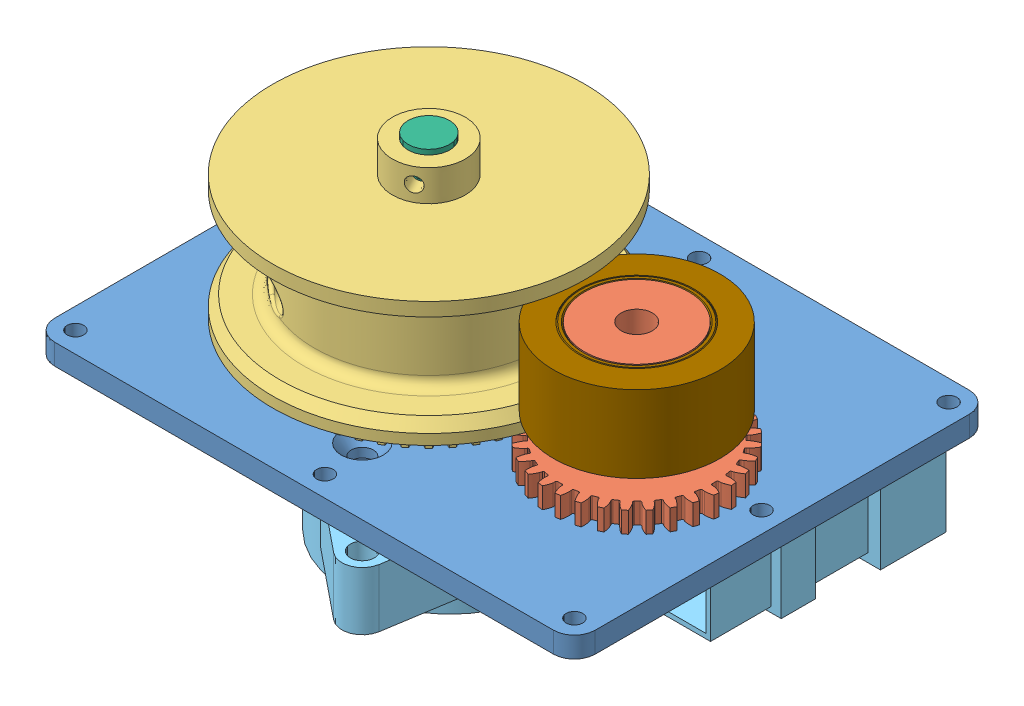
SolidWorks assembly DualRollerWinch, configuration Default. Lengths in mm.
Overall size (166.05 109.39 150.81).
9 component instances, 9 part files, 23 mates.
Components (placement in the parent):
- GearedWinchBaseplate-1: GearedWinchBaseplate [Default] at origin size (165.1 15.88 127)
- GearedWinchRoller-1: GearedWinchRoller [6325K18] at (44.45 6.35 6.35) x (-0.239605 0 0.97087) z (0 -1 0) size (54.09 54.09 37.12)
- GearedDrum-1: GearedDrum [6325K21] at (-19.05 12.7 6.35) x (0.881849 0 -0.471533) z (0 1 0) size (95.25 95.25 53.98)
- 13125K81 Chemical Resistant Shaft Seal-1: 13125K81 Chemical Resistant Shaft Seal [Default] at (-19.05 3.175 6.35) x (0.899798 0 0.436307) z (-0.436307 0 0.899798) size (17.46 3.17 17.46)
- 82-17001-1: 82-17001 [Default] at (-19.0498 -46.355 0.0007) x (-1 0 -0.000006) z (0.000006 0 -1) size (129.51 43.12 129.41)
- MazdaMotorWinchShaft-1: MazdaMotorWinchShaft [Default] at (-19.05 -20.725 6.35) x (0.881849 0 -0.471533) z (0.471533 0 0.881849) size (22.23 82.55 22.23)
- 6658K680_OIL-EMBEDDED SLEEVE BRNG-1: 6658K680_OIL-EMBEDDED SLEEVE BRNG [6658K68] at (-19.0498 -6.225 0.0007) x (1 0 0) z (0 1 0) size (12 12 8)
- 60355K707_BALL BEARING-1: 60355K707_BALL BEARING [60355K707] at (-19.05 -3.175 6.35) x (1 0 0) z (0 1 0) size (47.62 47.62 12.7)
- 2476K240_ROLLER-1: 2476K240_ROLLER [2476K24] at (44.45 43.4657 6.35) x (1 0 0) z (0 -1 0) size (50.8 50.8 23.47)
Mates (geometry in assembly coordinates):
- Concentric1: concentric anti-aligned: cylinder of GearedWinchBaseplate-1 through (44.45 6.35 6.35) axis (0 -1 0) radius 7.9375; cylinder of GearedWinchRoller-1 through (44.45 6.35 6.35) axis (0 1 0) radius 4.7625
- Concentric2: concentric aligned: cylinder of GearedWinchBaseplate-1 through (-19.05 -9.525 6.35) axis (0 1 0) radius 28.575; circle of GearedDrum-1
- Concentric3: concentric anti-aligned: cylinder of GearedWinchBaseplate-1 through (-19.05 3.175 0) axis (0 -1 0) radius 8.7312; cylinder of ? through (-19.05 3.175 0) axis (0 1 0) radius 14.2875
- GearMate1: gear = 50.8 : 76.2 mm: cylinder of GearedDrum-1 through (-19.05 6.35 6.35) axis (0 1 0) radius 39.751; cylinder of GearedWinchRoller-1 through (44.45 12.7 6.35) axis (0 -1 0) radius 27.051
- Coincident7: coincident anti-aligned: plane of GearedWinchBaseplate-1 through (-19.05 3.175 0) normal (0 -1 0); plane of ? through (-5.4729 3.175 -2.9344) normal (0 1 0)
- Concentric4: concentric anti-aligned: cylinder of GearedWinchBaseplate-1 through (-19.05 3.175 6.35) axis (0 1 0) radius 8.7312; cylinder of 13125K81 Chemical Resistant Shaft Seal-1 through (-19.05 3.175 6.35) axis (0 -1 0) radius 8.7312
- Coincident9: coincident anti-aligned: plane of GearedWinchBaseplate-1 through (0 6.35 0) normal (0 1 0); plane of GearedWinchRoller-1 through (44.45 6.35 6.35) normal (0 -1 0)
- Coincident10: coincident anti-aligned: plane of GearedWinchBaseplate-1 through (0 6.35 0) normal (0 1 0); plane of GearedDrum-1 through (-19.05 6.35 6.35) normal (0 -1 0)
- Coincident11: coincident aligned: plane of MazdaMotorWinchShaft-1 through (-19.05 -10.225 6.35) normal (0 -1 0); plane of 6658K680_OIL-EMBEDDED SLEEVE BRNG-1 through (-19.0498 -10.225 0.0007) normal (0 -1 0)
- Concentric6: concentric aligned: cylinder of 82-17001-1 through (-19.0498 -4.445 0.0007) axis (0 -1 0) radius 4; cylinder of 6658K680_OIL-EMBEDDED SLEEVE BRNG-1 through (-19.0498 -2.225 0.0007) axis (0 -1 0) radius 4
- Coincident12: coincident anti-aligned: plane of 82-17001-1 through (-19.0498 -10.225 0.0007) normal (0 1 0); plane of MazdaMotorWinchShaft-1 through (-19.05 -10.225 6.35) normal (0 -1 0)
- Concentric7: concentric anti-aligned: cylinder of ? through (-19.05 3.175 0) axis (0 1 0) radius 6.35; cylinder of MazdaMotorWinchShaft-1 through (-19.05 33.1064 0) axis (0 -1 0) radius 6.35
- Concentric8: concentric anti-aligned: cylinder of GearedWinchBaseplate-1 through (-19.05 3.175 6.35) axis (0 -1 0) radius 23.8125; circle of 60355K707_BALL BEARING-1
- Coincident13: coincident anti-aligned: plane of GearedWinchBaseplate-1 through (-19.05 3.175 6.35) normal (0 -1 0); plane of 60355K707_BALL BEARING-1 through (-19.05 3.175 -16.8275) normal (0 1 0)
- Concentric9: concentric anti-aligned: cylinder of GearedWinchBaseplate-1 through (-19.05 -9.525 6.35) axis (0 1 0) radius 28.575; cylinder of MazdaMotorWinchShaft-1 through (-19.05 1.5 6.35) axis (0 -1 0) radius 11.1125
- Concentric10: concentric anti-aligned: cone of GearedWinchBaseplate-1 through (-2.54 6.35 43.18) axis (0 -1 0); cylinder of 82-17001-1 through (-2.54 -40.005 43.18) axis (0 1 0) radius 3.683
- Distance1: distance = 22.225 mm anti-aligned: plane of 82-17001-1 through (-19.0498 -22.225 0.0007) normal (0 1 0); plane of GearedWinchBaseplate-1 through (0 0 0) normal (0 -1 0)
- Coincident16: coincident aligned: plane of GearedWinchBaseplate-1 through (0 6.35 0) normal (0 1 0); plane of 13125K81 Chemical Resistant Shaft Seal-1 through (-26.1921 6.35 2.8868) normal (0 1 0)
- Parallel1: parallel aligned: cylinder of GearedDrum-1 through (-13.8101 55.5625 16.1495) axis (0.471533 0 0.881849) radius 2.2479; cylinder of MazdaMotorWinchShaft-1 through (-16.0558 55.475 11.9497) axis (0.471533 0 0.881849) radius 1.7272
- Concentric12: concentric anti-aligned: cylinder of GearedWinchRoller-1 through (44.45 69.0563 6.35) axis (0 -1 0) radius 15.875; cylinder of ? through (44.45 19.8438 6.35) axis (0 1 0) radius 15.9004
- Coincident17: coincident aligned: plane of GearedWinchRoller-1 through (44.45 69.0563 6.35) normal (0 1 0); plane of ? through (44.45 69.0563 6.35) normal (0 1 0)
- Concentric14: concentric anti-aligned: cylinder of GearedWinchRoller-1 through (44.45 43.4657 6.35) axis (0 -1 0) radius 15.875; cylinder of 2476K240_ROLLER-1 through (44.45 19.9962 6.35) axis (0 1 0) radius 15.9004
- Coincident18: coincident aligned: plane of GearedWinchRoller-1 through (44.45 43.4657 6.35) normal (0 1 0); plane of 2476K240_ROLLER-1 through (44.45 43.4657 6.35) normal (0 1 0)
